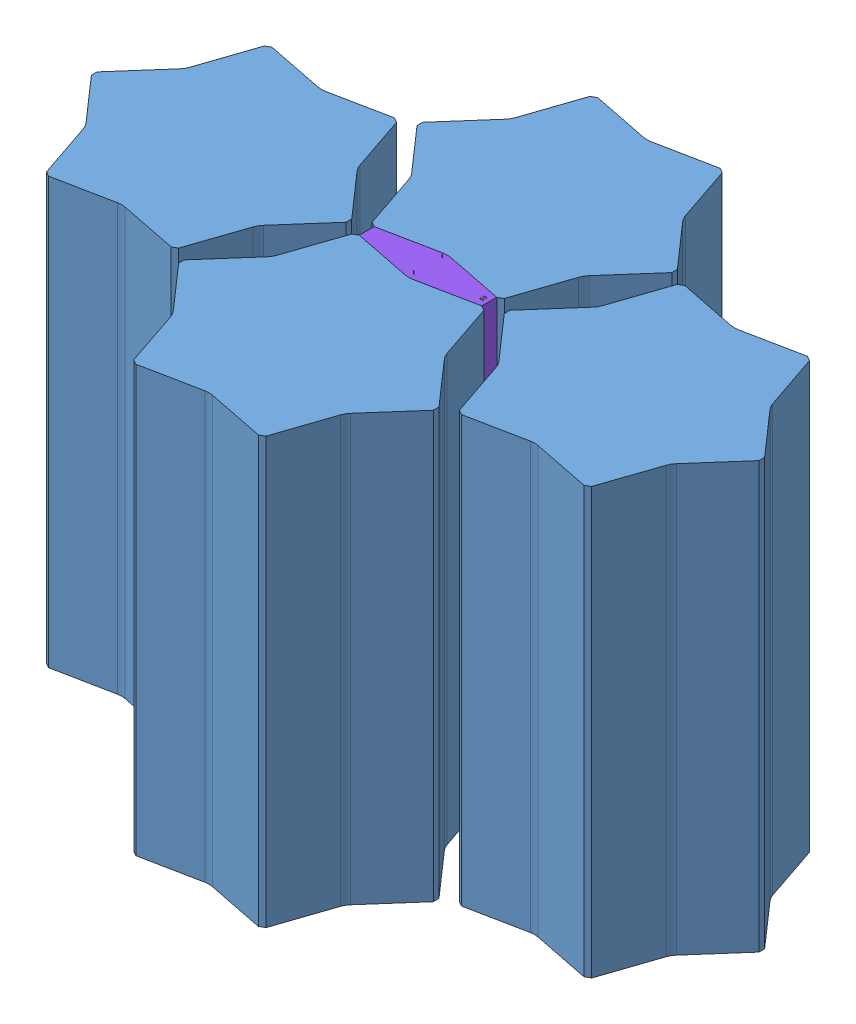
SolidWorks assembly Array-1, configuration 默认. Lengths in mm.
Overall size (2275.4 1330.46 1600.94).
246 component instances, 8 part files, 6 mates.
Components (placement in the parent):
- Container-IV-1: Container-IV [默认] at (57.4451 -9.9043 1320) size (790 1320 692.82)
- RealString-1: RealString [默认] at (54.4766 -598.7355 1609.6203) size (380 1330.46 350.65)
  - RealUnit-1: RealUnit [默认] at origin size (374.87 90.61 350.65)
    - BEGeDet-1: BEGeDet [默认] at (2.9686 -23.0613 80) size (80 40 80)
    - InnerShell-IV-1: InnerShell-IV [默认] at (2.9686 -23.1113 80) x (0.656103 0 0.754671) z (-0.754671 0 0.656103) size (89 50 89)
    - RealOuterShell-IV-Part-3: RealOuterShell-IV-Part [默认] at (2.9686 -24.1113 80) x (-1 0 0) z (0 0 -1) size (357.21 73.56 262.25)
    - RealOuterShell-IV-Part-4: RealOuterShell-IV-Part [默认] at (2.5967 -24.1114 80) x (1 0.000332 0) z (0 0 1) size (357.21 73.56 262.25)
    - Electronics-1: Electronics [默认] at (2.9686 -48.2113 80) x (-1 0 0) z (0 0 -1) size (21.21 85 89.7)
    - ConnectionUnit-1: ConnectionUnit [默认] at (157.8605 -24.8554 155) x (-1 -0.000332 0) z (0 0 -1) size (23 75 26.4)
      - ConnectionRod-IV-1: ConnectionRod-IV [默认] at (-16.742 6.238 75) size (23 75 14)
      - RealSiPMArray-1: RealSiPMArray [默认] at (-11.242 1.238 75) x (-1 0 0) z (0 0 -1) size (3.97 70 26.4)
    - ConnectionUnit-2: ConnectionUnit [默认] at (-152.295 -24.9069 5) size (23 75 26.4)
      - ConnectionRod-IV-1: ConnectionRod-IV [默认] at (-16.742 6.238 75) size (23 75 14)
      - RealSiPMArray-1: RealSiPMArray [默认] at (-11.242 1.238 75) x (-1 0 0) z (0 0 -1) size (3.97 70 26.4)
  - RealUnit-2: RealUnit [默认] at (0 65 0) size (374.87 90.61 350.65)
    - BEGeDet-1: BEGeDet [默认] at (2.9686 -23.0613 80) size (80 40 80)
    - InnerShell-IV-1: InnerShell-IV [默认] at (2.9686 -23.1113 80) x (0.656103 0 0.754671) z (-0.754671 0 0.656103) size (89 50 89)
    - RealOuterShell-IV-Part-3: RealOuterShell-IV-Part [默认] at (2.9686 -24.1113 80) x (-1 0 0) z (0 0 -1) size (357.21 73.56 262.25)
    - RealOuterShell-IV-Part-4: RealOuterShell-IV-Part [默认] at (2.5967 -24.1114 80) x (1 0.000332 0) z (0 0 1) size (357.21 73.56 262.25)
    - Electronics-1: Electronics [默认] at (2.9686 -48.2113 80) x (-1 0 0) z (0 0 -1) size (21.21 85 89.7)
    - ConnectionUnit-1: ConnectionUnit [默认] at (157.8605 -24.8554 155) x (-1 -0.000332 0) z (0 0 -1) size (23 75 26.4)
      - ConnectionRod-IV-1: ConnectionRod-IV [默认] at (-16.742 6.238 75) size (23 75 14)
      - RealSiPMArray-1: RealSiPMArray [默认] at (-11.242 1.238 75) x (-1 0 0) z (0 0 -1) size (3.97 70 26.4)
    - ConnectionUnit-2: ConnectionUnit [默认] at (-152.295 -24.9069 5) size (23 75 26.4)
      - ConnectionRod-IV-1: ConnectionRod-IV [默认] at (-16.742 6.238 75) size (23 75 14)
      - RealSiPMArray-1: RealSiPMArray [默认] at (-11.242 1.238 75) x (-1 0 0) z (0 0 -1) size (3.97 70 26.4)
  - RealUnit-3: RealUnit [默认] at (0 130 0) size (374.87 90.61 350.65)
    - BEGeDet-1: BEGeDet [默认] at (2.9686 -23.0613 80) size (80 40 80)
    - InnerShell-IV-1: InnerShell-IV [默认] at (2.9686 -23.1113 80) x (0.656103 0 0.754671) z (-0.754671 0 0.656103) size (89 50 89)
    - RealOuterShell-IV-Part-3: RealOuterShell-IV-Part [默认] at (2.9686 -24.1113 80) x (-1 0 0) z (0 0 -1) size (357.21 73.56 262.25)
    - RealOuterShell-IV-Part-4: RealOuterShell-IV-Part [默认] at (2.5967 -24.1114 80) x (1 0.000332 0) z (0 0 1) size (357.21 73.56 262.25)
    - Electronics-1: Electronics [默认] at (2.9686 -48.2113 80) x (-1 0 0) z (0 0 -1) size (21.21 85 89.7)
    - ConnectionUnit-1: ConnectionUnit [默认] at (157.8605 -24.8554 155) x (-1 -0.000332 0) z (0 0 -1) size (23 75 26.4)
      - ConnectionRod-IV-1: ConnectionRod-IV [默认] at (-16.742 6.238 75) size (23 75 14)
      - RealSiPMArray-1: RealSiPMArray [默认] at (-11.242 1.238 75) x (-1 0 0) z (0 0 -1) size (3.97 70 26.4)
    - ConnectionUnit-2: ConnectionUnit [默认] at (-152.295 -24.9069 5) size (23 75 26.4)
      - ConnectionRod-IV-1: ConnectionRod-IV [默认] at (-16.742 6.238 75) size (23 75 14)
      - RealSiPMArray-1: RealSiPMArray [默认] at (-11.242 1.238 75) x (-1 0 0) z (0 0 -1) size (3.97 70 26.4)
  - RealUnit-4: RealUnit [默认] at (0 195 0) size (374.87 90.61 350.65)
    - BEGeDet-1: BEGeDet [默认] at (2.9686 -23.0613 80) size (80 40 80)
    - InnerShell-IV-1: InnerShell-IV [默认] at (2.9686 -23.1113 80) x (0.656103 0 0.754671) z (-0.754671 0 0.656103) size (89 50 89)
    - RealOuterShell-IV-Part-3: RealOuterShell-IV-Part [默认] at (2.9686 -24.1113 80) x (-1 0 0) z (0 0 -1) size (357.21 73.56 262.25)
    - RealOuterShell-IV-Part-4: RealOuterShell-IV-Part [默认] at (2.5967 -24.1114 80) x (1 0.000332 0) z (0 0 1) size (357.21 73.56 262.25)
    - Electronics-1: Electronics [默认] at (2.9686 -48.2113 80) x (-1 0 0) z (0 0 -1) size (21.21 85 89.7)
    - ConnectionUnit-1: ConnectionUnit [默认] at (157.8605 -24.8554 155) x (-1 -0.000332 0) z (0 0 -1) size (23 75 26.4)
      - ConnectionRod-IV-1: ConnectionRod-IV [默认] at (-16.742 6.238 75) size (23 75 14)
      - RealSiPMArray-1: RealSiPMArray [默认] at (-11.242 1.238 75) x (-1 0 0) z (0 0 -1) size (3.97 70 26.4)
    - ConnectionUnit-2: ConnectionUnit [默认] at (-152.295 -24.9069 5) size (23 75 26.4)
      - ConnectionRod-IV-1: ConnectionRod-IV [默认] at (-16.742 6.238 75) size (23 75 14)
      - RealSiPMArray-1: RealSiPMArray [默认] at (-11.242 1.238 75) x (-1 0 0) z (0 0 -1) size (3.97 70 26.4)
  - RealUnit-5: RealUnit [默认] at (0 260 0) size (374.87 90.61 350.65)
    - BEGeDet-1: BEGeDet [默认] at (2.9686 -23.0613 80) size (80 40 80)
    - InnerShell-IV-1: InnerShell-IV [默认] at (2.9686 -23.1113 80) x (0.656103 0 0.754671) z (-0.754671 0 0.656103) size (89 50 89)
    - RealOuterShell-IV-Part-3: RealOuterShell-IV-Part [默认] at (2.9686 -24.1113 80) x (-1 0 0) z (0 0 -1) size (357.21 73.56 262.25)
    - RealOuterShell-IV-Part-4: RealOuterShell-IV-Part [默认] at (2.5967 -24.1114 80) x (1 0.000332 0) z (0 0 1) size (357.21 73.56 262.25)
    - Electronics-1: Electronics [默认] at (2.9686 -48.2113 80) x (-1 0 0) z (0 0 -1) size (21.21 85 89.7)
    - ConnectionUnit-1: ConnectionUnit [默认] at (157.8605 -24.8554 155) x (-1 -0.000332 0) z (0 0 -1) size (23 75 26.4)
      - ConnectionRod-IV-1: ConnectionRod-IV [默认] at (-16.742 6.238 75) size (23 75 14)
      - RealSiPMArray-1: RealSiPMArray [默认] at (-11.242 1.238 75) x (-1 0 0) z (0 0 -1) size (3.97 70 26.4)
    - ConnectionUnit-2: ConnectionUnit [默认] at (-152.295 -24.9069 5) size (23 75 26.4)
      - ConnectionRod-IV-1: ConnectionRod-IV [默认] at (-16.742 6.238 75) size (23 75 14)
      - RealSiPMArray-1: RealSiPMArray [默认] at (-11.242 1.238 75) x (-1 0 0) z (0 0 -1) size (3.97 70 26.4)
  - RealUnit-6: RealUnit [默认] at (0 325 0) size (374.87 90.61 350.65)
    - BEGeDet-1: BEGeDet [默认] at (2.9686 -23.0613 80) size (80 40 80)
    - InnerShell-IV-1: InnerShell-IV [默认] at (2.9686 -23.1113 80) x (0.656103 0 0.754671) z (-0.754671 0 0.656103) size (89 50 89)
    - RealOuterShell-IV-Part-3: RealOuterShell-IV-Part [默认] at (2.9686 -24.1113 80) x (-1 0 0) z (0 0 -1) size (357.21 73.56 262.25)
    - RealOuterShell-IV-Part-4: RealOuterShell-IV-Part [默认] at (2.5967 -24.1114 80) x (1 0.000332 0) z (0 0 1) size (357.21 73.56 262.25)
    - Electronics-1: Electronics [默认] at (2.9686 -48.2113 80) x (-1 0 0) z (0 0 -1) size (21.21 85 89.7)
    - ConnectionUnit-1: ConnectionUnit [默认] at (157.8605 -24.8554 155) x (-1 -0.000332 0) z (0 0 -1) size (23 75 26.4)
      - ConnectionRod-IV-1: ConnectionRod-IV [默认] at (-16.742 6.238 75) size (23 75 14)
      - RealSiPMArray-1: RealSiPMArray [默认] at (-11.242 1.238 75) x (-1 0 0) z (0 0 -1) size (3.97 70 26.4)
    - ConnectionUnit-2: ConnectionUnit [默认] at (-152.295 -24.9069 5) size (23 75 26.4)
      - ConnectionRod-IV-1: ConnectionRod-IV [默认] at (-16.742 6.238 75) size (23 75 14)
      - RealSiPMArray-1: RealSiPMArray [默认] at (-11.242 1.238 75) x (-1 0 0) z (0 0 -1) size (3.97 70 26.4)
  - RealUnit-7: RealUnit [默认] at (0 390 0) size (374.87 90.61 350.65)
    - BEGeDet-1: BEGeDet [默认] at (2.9686 -23.0613 80) size (80 40 80)
    - InnerShell-IV-1: InnerShell-IV [默认] at (2.9686 -23.1113 80) x (0.656103 0 0.754671) z (-0.754671 0 0.656103) size (89 50 89)
    - RealOuterShell-IV-Part-3: RealOuterShell-IV-Part [默认] at (2.9686 -24.1113 80) x (-1 0 0) z (0 0 -1) size (357.21 73.56 262.25)
    - RealOuterShell-IV-Part-4: RealOuterShell-IV-Part [默认] at (2.5967 -24.1114 80) x (1 0.000332 0) z (0 0 1) size (357.21 73.56 262.25)
    - Electronics-1: Electronics [默认] at (2.9686 -48.2113 80) x (-1 0 0) z (0 0 -1) size (21.21 85 89.7)
    - ConnectionUnit-1: ConnectionUnit [默认] at (157.8605 -24.8554 155) x (-1 -0.000332 0) z (0 0 -1) size (23 75 26.4)
      - ConnectionRod-IV-1: ConnectionRod-IV [默认] at (-16.742 6.238 75) size (23 75 14)
      - RealSiPMArray-1: RealSiPMArray [默认] at (-11.242 1.238 75) x (-1 0 0) z (0 0 -1) size (3.97 70 26.4)
    - ConnectionUnit-2: ConnectionUnit [默认] at (-152.295 -24.9069 5) size (23 75 26.4)
      - ConnectionRod-IV-1: ConnectionRod-IV [默认] at (-16.742 6.238 75) size (23 75 14)
      - RealSiPMArray-1: RealSiPMArray [默认] at (-11.242 1.238 75) x (-1 0 0) z (0 0 -1) size (3.97 70 26.4)
  - RealUnit-8: RealUnit [默认] at (0 455 0) size (374.87 90.61 350.65)
    - BEGeDet-1: BEGeDet [默认] at (2.9686 -23.0613 80) size (80 40 80)
    - InnerShell-IV-1: InnerShell-IV [默认] at (2.9686 -23.1113 80) x (0.656103 0 0.754671) z (-0.754671 0 0.656103) size (89 50 89)
    - RealOuterShell-IV-Part-3: RealOuterShell-IV-Part [默认] at (2.9686 -24.1113 80) x (-1 0 0) z (0 0 -1) size (357.21 73.56 262.25)
    - RealOuterShell-IV-Part-4: RealOuterShell-IV-Part [默认] at (2.5967 -24.1114 80) x (1 0.000332 0) z (0 0 1) size (357.21 73.56 262.25)
    - Electronics-1: Electronics [默认] at (2.9686 -48.2113 80) x (-1 0 0) z (0 0 -1) size (21.21 85 89.7)
    - ConnectionUnit-1: ConnectionUnit [默认] at (157.8605 -24.8554 155) x (-1 -0.000332 0) z (0 0 -1) size (23 75 26.4)
      - ConnectionRod-IV-1: ConnectionRod-IV [默认] at (-16.742 6.238 75) size (23 75 14)
      - RealSiPMArray-1: RealSiPMArray [默认] at (-11.242 1.238 75) x (-1 0 0) z (0 0 -1) size (3.97 70 26.4)
    - ConnectionUnit-2: ConnectionUnit [默认] at (-152.295 -24.9069 5) size (23 75 26.4)
      - ConnectionRod-IV-1: ConnectionRod-IV [默认] at (-16.742 6.238 75) size (23 75 14)
      - RealSiPMArray-1: RealSiPMArray [默认] at (-11.242 1.238 75) x (-1 0 0) z (0 0 -1) size (3.97 70 26.4)
  - RealUnit-9: RealUnit [默认] at (0 520 0) size (374.87 90.61 350.65)
    - BEGeDet-1: BEGeDet [默认] at (2.9686 -23.0613 80) size (80 40 80)
    - InnerShell-IV-1: InnerShell-IV [默认] at (2.9686 -23.1113 80) x (0.656103 0 0.754671) z (-0.754671 0 0.656103) size (89 50 89)
    - RealOuterShell-IV-Part-3: RealOuterShell-IV-Part [默认] at (2.9686 -24.1113 80) x (-1 0 0) z (0 0 -1) size (357.21 73.56 262.25)
    - RealOuterShell-IV-Part-4: RealOuterShell-IV-Part [默认] at (2.5967 -24.1114 80) x (1 0.000332 0) z (0 0 1) size (357.21 73.56 262.25)
    - Electronics-1: Electronics [默认] at (2.9686 -48.2113 80) x (-1 0 0) z (0 0 -1) size (21.21 85 89.7)
    - ConnectionUnit-1: ConnectionUnit [默认] at (157.8605 -24.8554 155) x (-1 -0.000332 0) z (0 0 -1) size (23 75 26.4)
      - ConnectionRod-IV-1: ConnectionRod-IV [默认] at (-16.742 6.238 75) size (23 75 14)
      - RealSiPMArray-1: RealSiPMArray [默认] at (-11.242 1.238 75) x (-1 0 0) z (0 0 -1) size (3.97 70 26.4)
    - ConnectionUnit-2: ConnectionUnit [默认] at (-152.295 -24.9069 5) size (23 75 26.4)
      - ConnectionRod-IV-1: ConnectionRod-IV [默认] at (-16.742 6.238 75) size (23 75 14)
      - RealSiPMArray-1: RealSiPMArray [默认] at (-11.242 1.238 75) x (-1 0 0) z (0 0 -1) size (3.97 70 26.4)
  - RealUnit-10: RealUnit [默认] at (0 585 0) size (374.87 90.61 350.65)
    - BEGeDet-1: BEGeDet [默认] at (2.9686 -23.0613 80) size (80 40 80)
    - InnerShell-IV-1: InnerShell-IV [默认] at (2.9686 -23.1113 80) x (0.656103 0 0.754671) z (-0.754671 0 0.656103) size (89 50 89)
    - RealOuterShell-IV-Part-3: RealOuterShell-IV-Part [默认] at (2.9686 -24.1113 80) x (-1 0 0) z (0 0 -1) size (357.21 73.56 262.25)
    - RealOuterShell-IV-Part-4: RealOuterShell-IV-Part [默认] at (2.5967 -24.1114 80) x (1 0.000332 0) z (0 0 1) size (357.21 73.56 262.25)
    - Electronics-1: Electronics [默认] at (2.9686 -48.2113 80) x (-1 0 0) z (0 0 -1) size (21.21 85 89.7)
    - ConnectionUnit-1: ConnectionUnit [默认] at (157.8605 -24.8554 155) x (-1 -0.000332 0) z (0 0 -1) size (23 75 26.4)
      - ConnectionRod-IV-1: ConnectionRod-IV [默认] at (-16.742 6.238 75) size (23 75 14)
      - RealSiPMArray-1: RealSiPMArray [默认] at (-11.242 1.238 75) x (-1 0 0) z (0 0 -1) size (3.97 70 26.4)
    - ConnectionUnit-2: ConnectionUnit [默认] at (-152.295 -24.9069 5) size (23 75 26.4)
      - ConnectionRod-IV-1: ConnectionRod-IV [默认] at (-16.742 6.238 75) size (23 75 14)
      - RealSiPMArray-1: RealSiPMArray [默认] at (-11.242 1.238 75) x (-1 0 0) z (0 0 -1) size (3.97 70 26.4)
  - RealUnit-11: RealUnit [默认] at (0 650 0) size (374.87 90.61 350.65)
    - BEGeDet-1: BEGeDet [默认] at (2.9686 -23.0613 80) size (80 40 80)
    - InnerShell-IV-1: InnerShell-IV [默认] at (2.9686 -23.1113 80) x (0.656103 0 0.754671) z (-0.754671 0 0.656103) size (89 50 89)
    - RealOuterShell-IV-Part-3: RealOuterShell-IV-Part [默认] at (2.9686 -24.1113 80) x (-1 0 0) z (0 0 -1) size (357.21 73.56 262.25)
    - RealOuterShell-IV-Part-4: RealOuterShell-IV-Part [默认] at (2.5967 -24.1114 80) x (1 0.000332 0) z (0 0 1) size (357.21 73.56 262.25)
    - Electronics-1: Electronics [默认] at (2.9686 -48.2113 80) x (-1 0 0) z (0 0 -1) size (21.21 85 89.7)
    - ConnectionUnit-1: ConnectionUnit [默认] at (157.8605 -24.8554 155) x (-1 -0.000332 0) z (0 0 -1) size (23 75 26.4)
      - ConnectionRod-IV-1: ConnectionRod-IV [默认] at (-16.742 6.238 75) size (23 75 14)
      - RealSiPMArray-1: RealSiPMArray [默认] at (-11.242 1.238 75) x (-1 0 0) z (0 0 -1) size (3.97 70 26.4)
    - ConnectionUnit-2: ConnectionUnit [默认] at (-152.295 -24.9069 5) size (23 75 26.4)
      - ConnectionRod-IV-1: ConnectionRod-IV [默认] at (-16.742 6.238 75) size (23 75 14)
      - RealSiPMArray-1: RealSiPMArray [默认] at (-11.242 1.238 75) x (-1 0 0) z (0 0 -1) size (3.97 70 26.4)
  - RealUnit-12: RealUnit [默认] at (0 715 0) size (374.87 90.61 350.65)
    - BEGeDet-1: BEGeDet [默认] at (2.9686 -23.0613 80) size (80 40 80)
    - InnerShell-IV-1: InnerShell-IV [默认] at (2.9686 -23.1113 80) x (0.656103 0 0.754671) z (-0.754671 0 0.656103) size (89 50 89)
    - RealOuterShell-IV-Part-3: RealOuterShell-IV-Part [默认] at (2.9686 -24.1113 80) x (-1 0 0) z (0 0 -1) size (357.21 73.56 262.25)
    - RealOuterShell-IV-Part-4: RealOuterShell-IV-Part [默认] at (2.5967 -24.1114 80) x (1 0.000332 0) z (0 0 1) size (357.21 73.56 262.25)
    - Electronics-1: Electronics [默认] at (2.9686 -48.2113 80) x (-1 0 0) z (0 0 -1) size (21.21 85 89.7)
    - ConnectionUnit-1: ConnectionUnit [默认] at (157.8605 -24.8554 155) x (-1 -0.000332 0) z (0 0 -1) size (23 75 26.4)
      - ConnectionRod-IV-1: ConnectionRod-IV [默认] at (-16.742 6.238 75) size (23 75 14)
      - RealSiPMArray-1: RealSiPMArray [默认] at (-11.242 1.238 75) x (-1 0 0) z (0 0 -1) size (3.97 70 26.4)
    - ConnectionUnit-2: ConnectionUnit [默认] at (-152.295 -24.9069 5) size (23 75 26.4)
      - ConnectionRod-IV-1: ConnectionRod-IV [默认] at (-16.742 6.238 75) size (23 75 14)
      - RealSiPMArray-1: RealSiPMArray [默认] at (-11.242 1.238 75) x (-1 0 0) z (0 0 -1) size (3.97 70 26.4)
  - RealUnit-13: RealUnit [默认] at (0 780 0) size (374.87 90.61 350.65)
    - BEGeDet-1: BEGeDet [默认] at (2.9686 -23.0613 80) size (80 40 80)
    - InnerShell-IV-1: InnerShell-IV [默认] at (2.9686 -23.1113 80) x (0.656103 0 0.754671) z (-0.754671 0 0.656103) size (89 50 89)
    - RealOuterShell-IV-Part-3: RealOuterShell-IV-Part [默认] at (2.9686 -24.1113 80) x (-1 0 0) z (0 0 -1) size (357.21 73.56 262.25)
    - RealOuterShell-IV-Part-4: RealOuterShell-IV-Part [默认] at (2.5967 -24.1114 80) x (1 0.000332 0) z (0 0 1) size (357.21 73.56 262.25)
    - Electronics-1: Electronics [默认] at (2.9686 -48.2113 80) x (-1 0 0) z (0 0 -1) size (21.21 85 89.7)
    - ConnectionUnit-1: ConnectionUnit [默认] at (157.8605 -24.8554 155) x (-1 -0.000332 0) z (0 0 -1) size (23 75 26.4)
      - ConnectionRod-IV-1: ConnectionRod-IV [默认] at (-16.742 6.238 75) size (23 75 14)
      - RealSiPMArray-1: RealSiPMArray [默认] at (-11.242 1.238 75) x (-1 0 0) z (0 0 -1) size (3.97 70 26.4)
    - ConnectionUnit-2: ConnectionUnit [默认] at (-152.295 -24.9069 5) size (23 75 26.4)
      - ConnectionRod-IV-1: ConnectionRod-IV [默认] at (-16.742 6.238 75) size (23 75 14)
      - RealSiPMArray-1: RealSiPMArray [默认] at (-11.242 1.238 75) x (-1 0 0) z (0 0 -1) size (3.97 70 26.4)
  - RealUnit-14: RealUnit [默认] at (0 845 0) size (374.87 90.61 350.65)
    - BEGeDet-1: BEGeDet [默认] at (2.9686 -23.0613 80) size (80 40 80)
    - InnerShell-IV-1: InnerShell-IV [默认] at (2.9686 -23.1113 80) x (0.656103 0 0.754671) z (-0.754671 0 0.656103) size (89 50 89)
    - RealOuterShell-IV-Part-3: RealOuterShell-IV-Part [默认] at (2.9686 -24.1113 80) x (-1 0 0) z (0 0 -1) size (357.21 73.56 262.25)
    - RealOuterShell-IV-Part-4: RealOuterShell-IV-Part [默认] at (2.5967 -24.1114 80) x (1 0.000332 0) z (0 0 1) size (357.21 73.56 262.25)
    - Electronics-1: Electronics [默认] at (2.9686 -48.2113 80) x (-1 0 0) z (0 0 -1) size (21.21 85 89.7)
    - ConnectionUnit-1: ConnectionUnit [默认] at (157.8605 -24.8554 155) x (-1 -0.000332 0) z (0 0 -1) size (23 75 26.4)
      - ConnectionRod-IV-1: ConnectionRod-IV [默认] at (-16.742 6.238 75) size (23 75 14)
      - RealSiPMArray-1: RealSiPMArray [默认] at (-11.242 1.238 75) x (-1 0 0) z (0 0 -1) size (3.97 70 26.4)
    - ConnectionUnit-2: ConnectionUnit [默认] at (-152.295 -24.9069 5) size (23 75 26.4)
      - ConnectionRod-IV-1: ConnectionRod-IV [默认] at (-16.742 6.238 75) size (23 75 14)
      - RealSiPMArray-1: RealSiPMArray [默认] at (-11.242 1.238 75) x (-1 0 0) z (0 0 -1) size (3.97 70 26.4)
  - RealUnit-15: RealUnit [默认] at (0 910 0) size (374.87 90.61 350.65)
    - BEGeDet-1: BEGeDet [默认] at (2.9686 -23.0613 80) size (80 40 80)
    - InnerShell-IV-1: InnerShell-IV [默认] at (2.9686 -23.1113 80) x (0.656103 0 0.754671) z (-0.754671 0 0.656103) size (89 50 89)
    - RealOuterShell-IV-Part-3: RealOuterShell-IV-Part [默认] at (2.9686 -24.1113 80) x (-1 0 0) z (0 0 -1) size (357.21 73.56 262.25)
    - RealOuterShell-IV-Part-4: RealOuterShell-IV-Part [默认] at (2.5967 -24.1114 80) x (1 0.000332 0) z (0 0 1) size (357.21 73.56 262.25)
    - Electronics-1: Electronics [默认] at (2.9686 -48.2113 80) x (-1 0 0) z (0 0 -1) size (21.21 85 89.7)
    - ConnectionUnit-1: ConnectionUnit [默认] at (157.8605 -24.8554 155) x (-1 -0.000332 0) z (0 0 -1) size (23 75 26.4)
      - ConnectionRod-IV-1: ConnectionRod-IV [默认] at (-16.742 6.238 75) size (23 75 14)
      - RealSiPMArray-1: RealSiPMArray [默认] at (-11.242 1.238 75) x (-1 0 0) z (0 0 -1) size (3.97 70 26.4)
    - ConnectionUnit-2: ConnectionUnit [默认] at (-152.295 -24.9069 5) size (23 75 26.4)
      - ConnectionRod-IV-1: ConnectionRod-IV [默认] at (-16.742 6.238 75) size (23 75 14)
      - RealSiPMArray-1: RealSiPMArray [默认] at (-11.242 1.238 75) x (-1 0 0) z (0 0 -1) size (3.97 70 26.4)
  - RealUnit-16: RealUnit [默认] at (0 975 0) size (374.87 90.61 350.65)
    - BEGeDet-1: BEGeDet [默认] at (2.9686 -23.0613 80) size (80 40 80)
    - InnerShell-IV-1: InnerShell-IV [默认] at (2.9686 -23.1113 80) x (0.656103 0 0.754671) z (-0.754671 0 0.656103) size (89 50 89)
    - RealOuterShell-IV-Part-3: RealOuterShell-IV-Part [默认] at (2.9686 -24.1113 80) x (-1 0 0) z (0 0 -1) size (357.21 73.56 262.25)
    - RealOuterShell-IV-Part-4: RealOuterShell-IV-Part [默认] at (2.5967 -24.1114 80) x (1 0.000332 0) z (0 0 1) size (357.21 73.56 262.25)
    - Electronics-1: Electronics [默认] at (2.9686 -48.2113 80) x (-1 0 0) z (0 0 -1) size (21.21 85 89.7)
    - ConnectionUnit-1: ConnectionUnit [默认] at (157.8605 -24.8554 155) x (-1 -0.000332 0) z (0 0 -1) size (23 75 26.4)
      - ConnectionRod-IV-1: ConnectionRod-IV [默认] at (-16.742 6.238 75) size (23 75 14)
      - RealSiPMArray-1: RealSiPMArray [默认] at (-11.242 1.238 75) x (-1 0 0) z (0 0 -1) size (3.97 70 26.4)
    - ConnectionUnit-2: ConnectionUnit [默认] at (-152.295 -24.9069 5) size (23 75 26.4)
      - ConnectionRod-IV-1: ConnectionRod-IV [默认] at (-16.742 6.238 75) size (23 75 14)
      - RealSiPMArray-1: RealSiPMArray [默认] at (-11.242 1.238 75) x (-1 0 0) z (0 0 -1) size (3.97 70 26.4)
  - RealUnit-17: RealUnit [默认] at (0 1040 0) size (374.87 90.61 350.65)
    - BEGeDet-1: BEGeDet [默认] at (2.9686 -23.0613 80) size (80 40 80)
    - InnerShell-IV-1: InnerShell-IV [默认] at (2.9686 -23.1113 80) x (0.656103 0 0.754671) z (-0.754671 0 0.656103) size (89 50 89)
    - RealOuterShell-IV-Part-3: RealOuterShell-IV-Part [默认] at (2.9686 -24.1113 80) x (-1 0 0) z (0 0 -1) size (357.21 73.56 262.25)
    - RealOuterShell-IV-Part-4: RealOuterShell-IV-Part [默认] at (2.5967 -24.1114 80) x (1 0.000332 0) z (0 0 1) size (357.21 73.56 262.25)
    - Electronics-1: Electronics [默认] at (2.9686 -48.2113 80) x (-1 0 0) z (0 0 -1) size (21.21 85 89.7)
    - ConnectionUnit-1: ConnectionUnit [默认] at (157.8605 -24.8554 155) x (-1 -0.000332 0) z (0 0 -1) size (23 75 26.4)
      - ConnectionRod-IV-1: ConnectionRod-IV [默认] at (-16.742 6.238 75) size (23 75 14)
      - RealSiPMArray-1: RealSiPMArray [默认] at (-11.242 1.238 75) x (-1 0 0) z (0 0 -1) size (3.97 70 26.4)
    - ConnectionUnit-2: ConnectionUnit [默认] at (-152.295 -24.9069 5) size (23 75 26.4)
      - ConnectionRod-IV-1: ConnectionRod-IV [默认] at (-16.742 6.238 75) size (23 75 14)
      - RealSiPMArray-1: RealSiPMArray [默认] at (-11.242 1.238 75) x (-1 0 0) z (0 0 -1) size (3.97 70 26.4)
  - RealUnit-18: RealUnit [默认] at (0 1105 0) size (374.87 90.61 350.65)
    - BEGeDet-1: BEGeDet [默认] at (2.9686 -23.0613 80) size (80 40 80)
    - InnerShell-IV-1: InnerShell-IV [默认] at (2.9686 -23.1113 80) x (0.656103 0 0.754671) z (-0.754671 0 0.656103) size (89 50 89)
    - RealOuterShell-IV-Part-3: RealOuterShell-IV-Part [默认] at (2.9686 -24.1113 80) x (-1 0 0) z (0 0 -1) size (357.21 73.56 262.25)
    - RealOuterShell-IV-Part-4: RealOuterShell-IV-Part [默认] at (2.5967 -24.1114 80) x (1 0.000332 0) z (0 0 1) size (357.21 73.56 262.25)
    - Electronics-1: Electronics [默认] at (2.9686 -48.2113 80) x (-1 0 0) z (0 0 -1) size (21.21 85 89.7)
    - ConnectionUnit-1: ConnectionUnit [默认] at (157.8605 -24.8554 155) x (-1 -0.000332 0) z (0 0 -1) size (23 75 26.4)
      - ConnectionRod-IV-1: ConnectionRod-IV [默认] at (-16.742 6.238 75) size (23 75 14)
      - RealSiPMArray-1: RealSiPMArray [默认] at (-11.242 1.238 75) x (-1 0 0) z (0 0 -1) size (3.97 70 26.4)
    - ConnectionUnit-2: ConnectionUnit [默认] at (-152.295 -24.9069 5) size (23 75 26.4)
      - ConnectionRod-IV-1: ConnectionRod-IV [默认] at (-16.742 6.238 75) size (23 75 14)
      - RealSiPMArray-1: RealSiPMArray [默认] at (-11.242 1.238 75) x (-1 0 0) z (0 0 -1) size (3.97 70 26.4)
  - RealUnit-19: RealUnit [默认] at (0 1170 0) size (374.87 90.61 350.65)
    - BEGeDet-1: BEGeDet [默认] at (2.9686 -23.0613 80) size (80 40 80)
    - InnerShell-IV-1: InnerShell-IV [默认] at (2.9686 -23.1113 80) x (0.656103 0 0.754671) z (-0.754671 0 0.656103) size (89 50 89)
    - RealOuterShell-IV-Part-3: RealOuterShell-IV-Part [默认] at (2.9686 -24.1113 80) x (-1 0 0) z (0 0 -1) size (357.21 73.56 262.25)
    - RealOuterShell-IV-Part-4: RealOuterShell-IV-Part [默认] at (2.5967 -24.1114 80) x (1 0.000332 0) z (0 0 1) size (357.21 73.56 262.25)
    - Electronics-1: Electronics [默认] at (2.9686 -48.2113 80) x (-1 0 0) z (0 0 -1) size (21.21 85 89.7)
    - ConnectionUnit-1: ConnectionUnit [默认] at (157.8605 -24.8554 155) x (-1 -0.000332 0) z (0 0 -1) size (23 75 26.4)
      - ConnectionRod-IV-1: ConnectionRod-IV [默认] at (-16.742 6.238 75) size (23 75 14)
      - RealSiPMArray-1: RealSiPMArray [默认] at (-11.242 1.238 75) x (-1 0 0) z (0 0 -1) size (3.97 70 26.4)
    - ConnectionUnit-2: ConnectionUnit [默认] at (-152.295 -24.9069 5) size (23 75 26.4)
      - ConnectionRod-IV-1: ConnectionRod-IV [默认] at (-16.742 6.238 75) size (23 75 14)
      - RealSiPMArray-1: RealSiPMArray [默认] at (-11.242 1.238 75) x (-1 0 0) z (0 0 -1) size (3.97 70 26.4)
  - RealUnit-20: RealUnit [默认] at (0 1235 0) size (374.87 90.61 350.65)
    - BEGeDet-1: BEGeDet [默认] at (2.9686 -23.0613 80) size (80 40 80)
    - InnerShell-IV-1: InnerShell-IV [默认] at (2.9686 -23.1113 80) x (0.656103 0 0.754671) z (-0.754671 0 0.656103) size (89 50 89)
    - RealOuterShell-IV-Part-3: RealOuterShell-IV-Part [默认] at (2.9686 -24.1113 80) x (-1 0 0) z (0 0 -1) size (357.21 73.56 262.25)
    - RealOuterShell-IV-Part-4: RealOuterShell-IV-Part [默认] at (2.5967 -24.1114 80) x (1 0.000332 0) z (0 0 1) size (357.21 73.56 262.25)
    - Electronics-1: Electronics [默认] at (2.9686 -48.2113 80) x (-1 0 0) z (0 0 -1) size (21.21 85 89.7)
    - ConnectionUnit-1: ConnectionUnit [默认] at (157.8605 -24.8554 155) x (-1 -0.000332 0) z (0 0 -1) size (23 75 26.4)
      - ConnectionRod-IV-1: ConnectionRod-IV [默认] at (-16.742 6.238 75) size (23 75 14)
      - RealSiPMArray-1: RealSiPMArray [默认] at (-11.242 1.238 75) x (-1 0 0) z (0 0 -1) size (3.97 70 26.4)
    - ConnectionUnit-2: ConnectionUnit [默认] at (-152.295 -24.9069 5) size (23 75 26.4)
      - ConnectionRod-IV-1: ConnectionRod-IV [默认] at (-16.742 6.238 75) size (23 75 14)
      - RealSiPMArray-1: RealSiPMArray [默认] at (-11.242 1.238 75) x (-1 0 0) z (0 0 -1) size (3.97 70 26.4)
  - StringBox-IV-1: StringBox-IV [默认] at (2.9686 588.8311 80) size (380 1320 120)
- Container-IV-5: Container-IV [默认] at (57.4451 -9.9043 2059.2407) x (-0.5 0 -0.866025) z (0.866025 0 -0.5) size (790 1320 692.82)
- Container-IV-3: Container-IV [默认] at (-582.7561 -9.9043 1689.6203) x (0.5 0 -0.866025) z (0.866025 0 0.5) size (790 1320 692.82)
- Container-IV-4: Container-IV [默认] at (697.6464 -9.9043 1689.6203) x (0.5 0 0.866025) z (-0.866025 0 0.5) size (790 1320 692.82)
Mates (geometry in assembly coordinates):
- 重合1: coincident aligned: plane of SArContainer-IV-1 through (57.4451 -669.9043 1320) normal (0 -1 0); plane of RealString-1/StringBox-IV-1 through (57.4451 -669.9043 1689.6203) normal (0 -1 0)
- 重合2: coincident anti-aligned: plane of SArContainer-IV-1 through (247.4451 -669.9043 1666.4102) normal (-0.196 0 0.980604); plane of RealString-1/StringBox-IV-1 through (239.4051 640.0957 1664.8032) normal (0.196 0 -0.980604)
- 重合3: coincident anti-aligned: plane of SArContainer-IV-1 through (45.6851 -669.9043 1630.7841) normal (0.196 0 0.980604); plane of RealString-1/StringBox-IV-1 through (45.6851 640.0957 1630.7841) normal (-0.196 0 -0.980604)
- 重合4: coincident aligned: plane of SArContainer-IV-1 through (57.4451 -669.9043 1320) normal (0 -1 0); plane of SArContainer-IV-2 through (57.4451 -669.9043 2059.2407) normal (0 -1 0)
- 重合10: coincident anti-aligned: plane of RealString-1/StringBox-IV-1 through (69.2051 640.0957 1748.4566) normal (0.196 0 0.980604); plane of SArContainer-IV-2 through (69.2051 -669.9043 1748.4566) normal (-0.196 0 -0.980604)
- 重合11: coincident anti-aligned: plane of RealString-1/StringBox-IV-1 through (-124.5149 640.0957 1714.4375) normal (-0.196 0 0.980604); plane of SArContainer-IV-2 through (-132.5549 -669.9043 1712.8305) normal (0.196 0 -0.980604)
